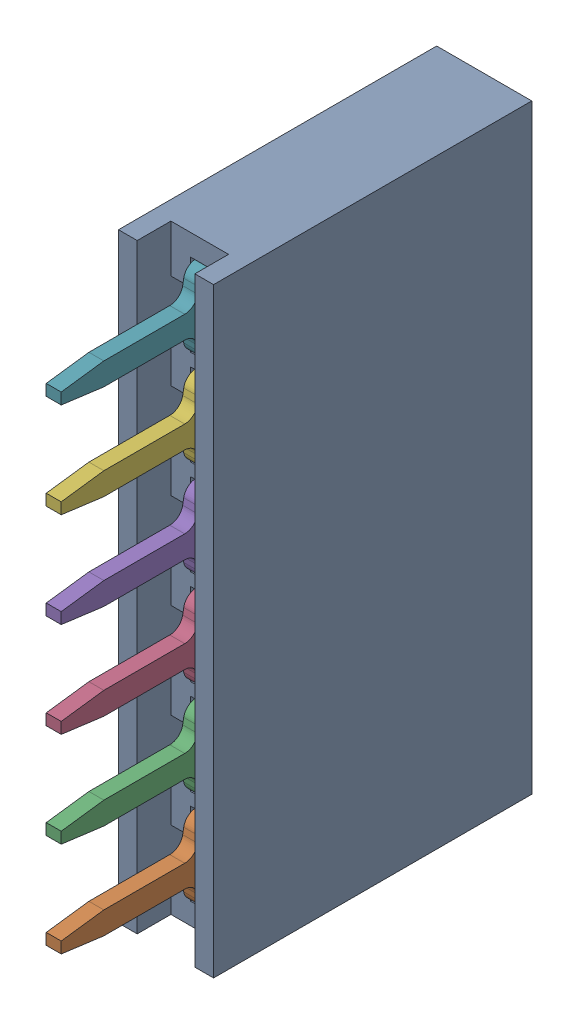
SolidWorks assembly H4_1.step, configuration Default. Lengths in mm.
Overall size (2.54 16.04 11.5).
8 component instances, 2 part files, 0 mates.
Components (placement in the parent):
- DS1023-1x6SF11_1.step-3: DS1023-1x6SF11_1.step [Default] at (465.8362 321.818 -1.647) x (0 1 0) z (0 0 -1) size (16.04 2.54 11.5)
  - body_3.step-8: body_3.step [Default] at origin size (16.04 2.54 8.5)
  - contact_1.step-51: contact_1.step [Default] at origin size (2.3 0.4 9)
  - contact_1.step-52: contact_1.step [Default] at (2.54 0 0) size (2.3 0.4 9)
  - contact_1.step-55: contact_1.step [Default] at (5.08 0 0) size (2.3 0.4 9)
  - contact_1.step-56: contact_1.step [Default] at (7.62 0 0) size (2.3 0.4 9)
  - contact_1.step-57: contact_1.step [Default] at (10.16 0 0) size (2.3 0.4 9)
  - contact_1.step-58: contact_1.step [Default] at (12.7 0 0) size (2.3 0.4 9)
